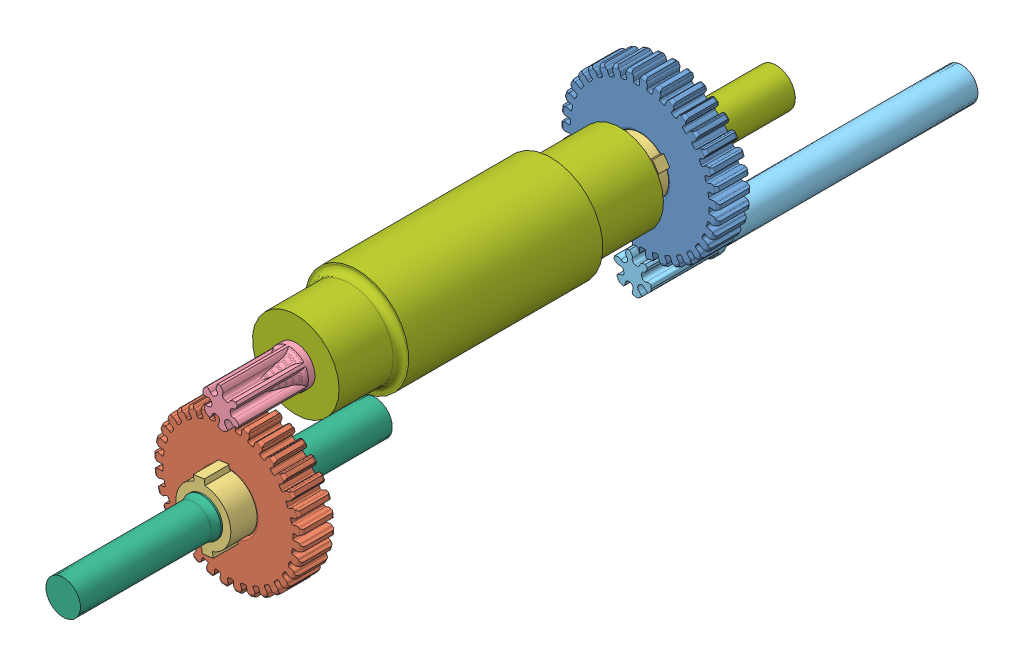
SolidWorks assembly GEAR2, configuration Default. Lengths in mm.
Overall size (63.57 80.78 259.29).
10 component instances, 9 part files, 23 mates.
Components (placement in the parent):
- drill-1: drill [Default] at (-24.644 14.5009 -121.9303) size (76.2 76.2 76.2) (hidden)
- 34 Tooth Gear-1: 34 Tooth Gear [Default] at (-24.644 66.8679 -59.1841) x (0 0 -1) z (0.560779 -0.827965 0) size (9.5 45.81 45.73)
- 32 Tooth Gear-1: 32 Tooth Gear [Default] at (-24.644 42.2934 50.2099) x (0 0 1) z (-0.990324 -0.138777 0) size (9.51 43.27 43.27)
- Bushing GAB20A-1: Bushing GAB20A [Default] at (-24.644 66.8679 -70.3831) x (0 0 1) z (-0.560779 0.827965 0) size (19.05 18.72 15.88)
- Bushing GAB20A-2: Bushing GAB20A [Default] at (-24.644 42.2934 52.3689) x (0 0 1) z (0.990324 0.138777 0) size (19.05 18.72 15.88)
- 6 Tooth Pinion 1-2: 6 Tooth Pinion 1 [Default] at (-24.644 66.8679 65.2909) x (0 0 -1) z (0.585018 -0.81102 0) size (59.69 11.6 11.05)
- case-1: case [Default] at (-24.644 53.8709 -83.8303) x (-1 0 0) z (0 0 -1) size (53.03 78.74 177.8) (hidden)
- 6 Tooth Pinion 2-1: 6 Tooth Pinion 2 [Default] at (-24.644 41.0234 -53.5011) x (0 0 -1) z (0.968964 0.2472 0) size (94.95 11.6 11.05)
- OUTPUTSHAFT2-1: OUTPUTSHAFT2 [Default] at (-24.644 42.2934 61.8579) x (-0.923728 -0.383049 0) z (0 0 -1) size (11.13 11.13 90)
- IntermediateShaft2-1: IntermediateShaft2 [Default] at (-24.644 66.8679 -48.8831) x (-0.979273 0.202543 0) z (0 0 1) size (30 30 138.6)
Mates (geometry in assembly coordinates):
- Concentric4: concentric anti-aligned: circle of 34 Tooth Gear-1; circle of Bushing GAB20A-1
- Parallel2: parallel anti-aligned: line of 34 Tooth Gear-1 through (-15.8918 70.8631 -54.4851) axis (-0.560779 0.827965 0); line of Bushing GAB20A-1 through (-17.7845 73.4312 -51.3331) axis (0.560779 -0.827965 0)
- Distance4: distance = 6.5 mm aligned: plane of Bushing GAB20A-1 through (-24.644 66.8679 -70.3831) normal (0 0 -1); plane of 34 Tooth Gear-1 through (-9.5956 80.3943 -63.8831) normal (0 0 -1)
- Concentric8: concentric anti-aligned: circle of 32 Tooth Gear-1; circle of Bushing GAB20A-2
- Distance7: distance = 2.54 mm aligned: plane of 32 Tooth Gear-1 through (-29.9862 60.4916 54.9089) normal (0 0 -1); plane of Bushing GAB20A-2 through (-24.644 42.2934 52.3689) normal (0 0 -1)
- Parallel4: parallel anti-aligned: line of 32 Tooth Gear-1 through (-24.9121 32.6763 54.9089) axis (0.990324 0.138777 0); line of Bushing GAB20A-2 through (-21.7729 33.2444 52.3689) axis (-0.990324 -0.138777 0)
- GearMate2: gear = 152.4 : 812.8 mm: circle of 32 Tooth Gear-1; circle of 6 Tooth Pinion 1-2
- Concentric21: concentric aligned: circle of drill-1; circle of 6 Tooth Pinion 2-1
- GearMate5: gear = 152.4 : 863.6 mm: circle of 34 Tooth Gear-1; circle of 6 Tooth Pinion 2-1
- Concentric22: concentric anti-aligned: cylinder of Bushing GAB20A-2 through (-24.644 42.2934 87.1524) axis (0 0 -1) radius 5.5626; cylinder of OUTPUTSHAFT2-1 through (-24.644 42.2934 21.8579) axis (0 0 1) radius 5
- Distance9: distance = 37.75 mm aligned: plane of OUTPUTSHAFT2-1 through (-24.644 42.2934 21.8579) normal (0 0 -1); plane of assembly through (0 0 59.6079) normal (0 0 -1)
- Concentric23: concentric aligned: cylinder of 6 Tooth Pinion 1-2 through (-24.644 66.8679 -28.6383) axis (0 0 1) radius 4.753; cylinder of IntermediateShaft2-1 through (-24.644 66.8679 -15.2831) axis (0 0 1) radius 4.755
- Coincident33: coincident anti-aligned: plane of 6 Tooth Pinion 1-2 through (-24.644 66.8679 44.7169) normal (0 0 -1); plane of IntermediateShaft2-1 through (-24.644 66.8679 44.7169) normal (0 0 1)
- Distance10: distance = 30 mm aligned: plane of 34 Tooth Gear-1 through (-9.5956 80.3943 -63.8831) normal (0 0 -1); plane of IntermediateShaft2-1 through (-24.644 66.8679 -93.8831) normal (0 0 -1)
- Distance12: distance = 2 mm aligned: plane of 34 Tooth Gear-1 through (-9.5956 80.3943 -54.4851) normal (0 0 1); plane of 6 Tooth Pinion 2-1 through (-24.644 41.0234 -52.4851) normal (0 0 1)
- Distance13: distance = 2 mm aligned: plane of 32 Tooth Gear-1 through (-29.9862 60.4916 64.3069) normal (0 0 1); plane of 6 Tooth Pinion 1-2 through (-24.644 66.8679 66.3069) normal (0 0 1)
- Concentric24: concentric anti-aligned: cylinder of Bushing GAB20A-1 through (-24.644 66.8679 -35.5996) axis (0 0 -1) radius 5.5626; cylinder of IntermediateShaft2-1 through (-24.644 66.8679 -93.8831) axis (0 0 1) radius 5.565
- Concentric25: concentric aligned: cylinder of drill-1 through (-24.644 66.8679 -156.2203) axis (0 0 1) radius 5.5626; cylinder of IntermediateShaft2-1 through (-24.644 66.8679 -93.8831) axis (0 0 1) radius 5.565
- Distance15: distance = 25.5 mm anti-aligned: plane of drill-1 through (-24.644 14.5009 -121.9303) normal (0 0 1); plane of 6 Tooth Pinion 2-1 through (-24.644 41.0234 -147.4303) normal (0 0 -1)
- Concentric26: concentric anti-aligned: circle of drill-1; circle of OUTPUTSHAFT2-1
- Concentric28: concentric anti-aligned: circle of 6 Tooth Pinion 1-2; circle of IntermediateShaft2-1
- Concentric29: concentric aligned: circle of Bushing GAB20A-1; circle of IntermediateShaft2-1
- Concentric30: concentric aligned: circle of case-1; circle of OUTPUTSHAFT2-1
